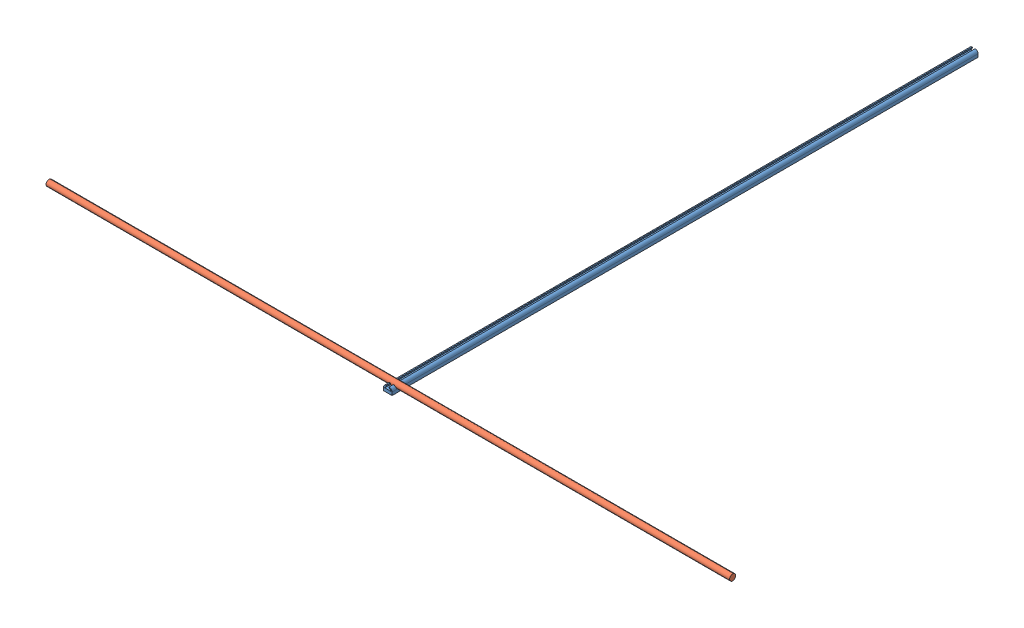
SolidWorks assembly Assem1, configuration Default. Lengths in mm.
Overall size (711.2 9.07 609.6).
2 component instances, 2 part files, 0 mates.
Components (placement in the parent):
- Twack-1: Twack [Default] at (-60.4644 16.2359 -284.9858) size (8.89 6.3 609.6)
- Metal rod 2ft-1: Metal rod 2ft [Default] at (-420.3759 20.5416 317.0956) size (711.2 6.35 6.35)
